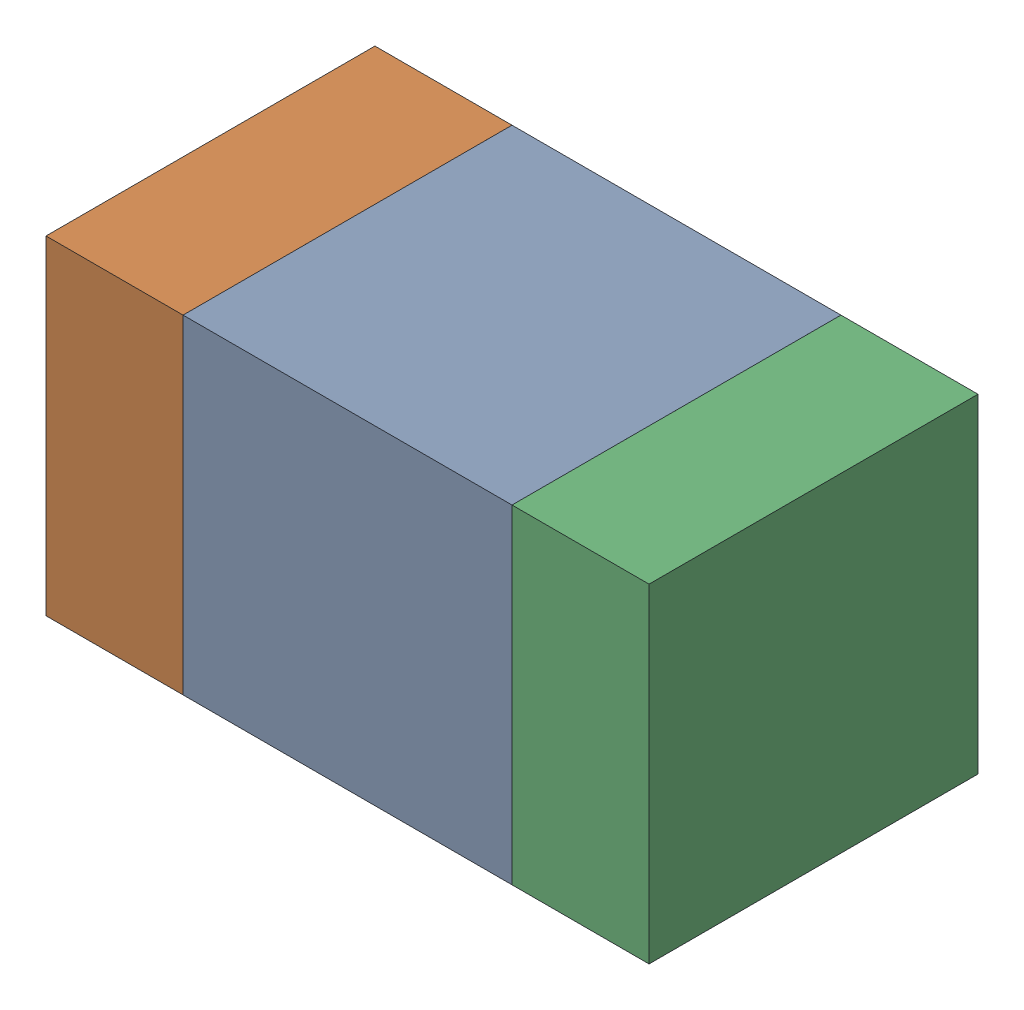
SolidWorks assembly C307_1PCB, configuration Default. Lengths in mm.
Overall size (1.1 0.6 0.6).
6 component instances, 2 part files, 0 mates.
Components (placement in the parent):
- 761606048-1: 761606048 [Default] at (130.8 113 0) size (0.6 0.6 0.6)
  - Extruded_9-1: Extruded_9 [Default] at origin size (0.6 0.6 0.6)
- 854785160-1: 854785160 [Default] at (130.375 113 0) size (0.25 0.6 0.6)
  - Extruded_19-1: Extruded_19 [Default] at origin size (0.25 0.6 0.6)
- 854785160-2: 854785160 [Default] at (131.225 113 0) size (0.25 0.6 0.6)
  - Extruded_19-1: Extruded_19 [Default] at origin size (0.25 0.6 0.6)
